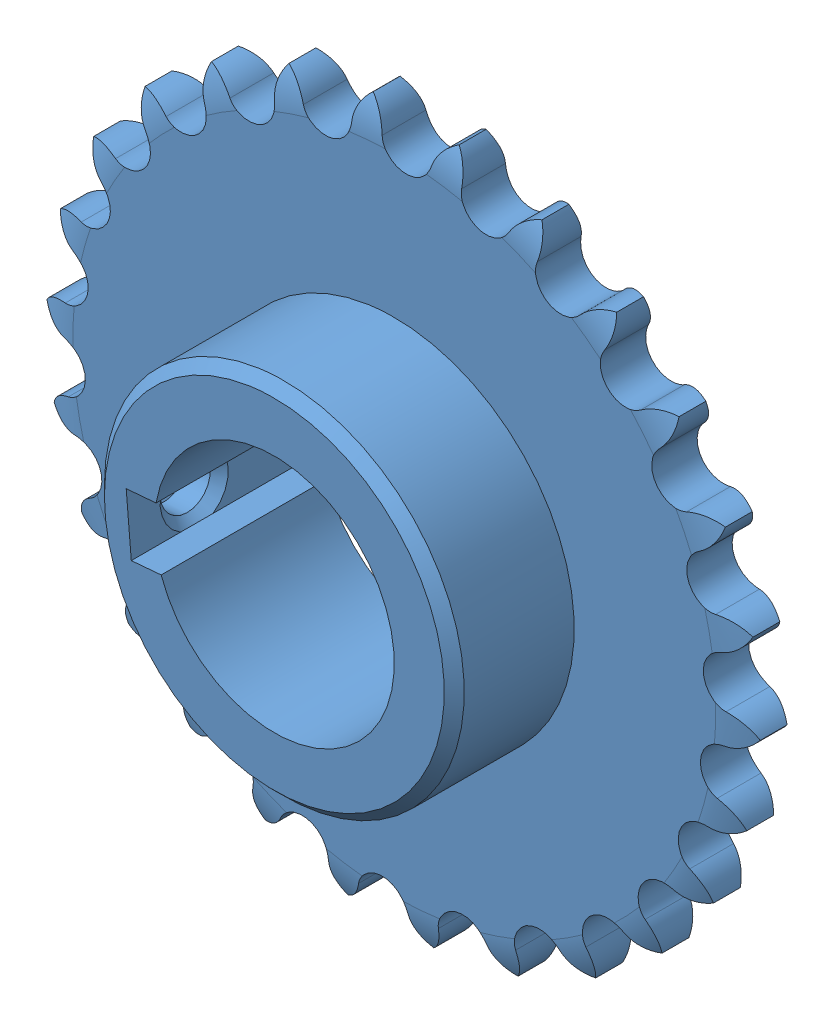
SolidWorks assembly sprocket 1, configuration Default. Lengths in mm.
Overall size (121.76 122.52 26.52).
2 component instances, 1 part files, 2 mates.
Components (placement in the parent):
- Chain A-1: Chain A [Default] at (-3.9373 5.8722 -1.9118) (suppressed, hidden)
- Sprocket-2: Sprocket [Default] at (240.2692 170.457 272.397) x (-0.084982 0.996383 0) z (0 0 1) size (113.36 112.54 26.52)
Mates (geometry in assembly coordinates):
- Width2: width: plane of Sprocket-2 through (240.2692 170.457 279.6106) normal (0 0 1); plane of Sprocket-2 through (240.2692 170.457 272.397) normal (0 0 -1); plane of ? through (208.4289 228.0374 268.7252) normal (0 0 -1); plane of ? through (208.4289 228.0374 283.2825) normal (0 0 1)
- Coincident2: coincident: line of ?; axis of Sprocket-2 through (240.2692 170.457 298.6606) axis (0 0 -1)
